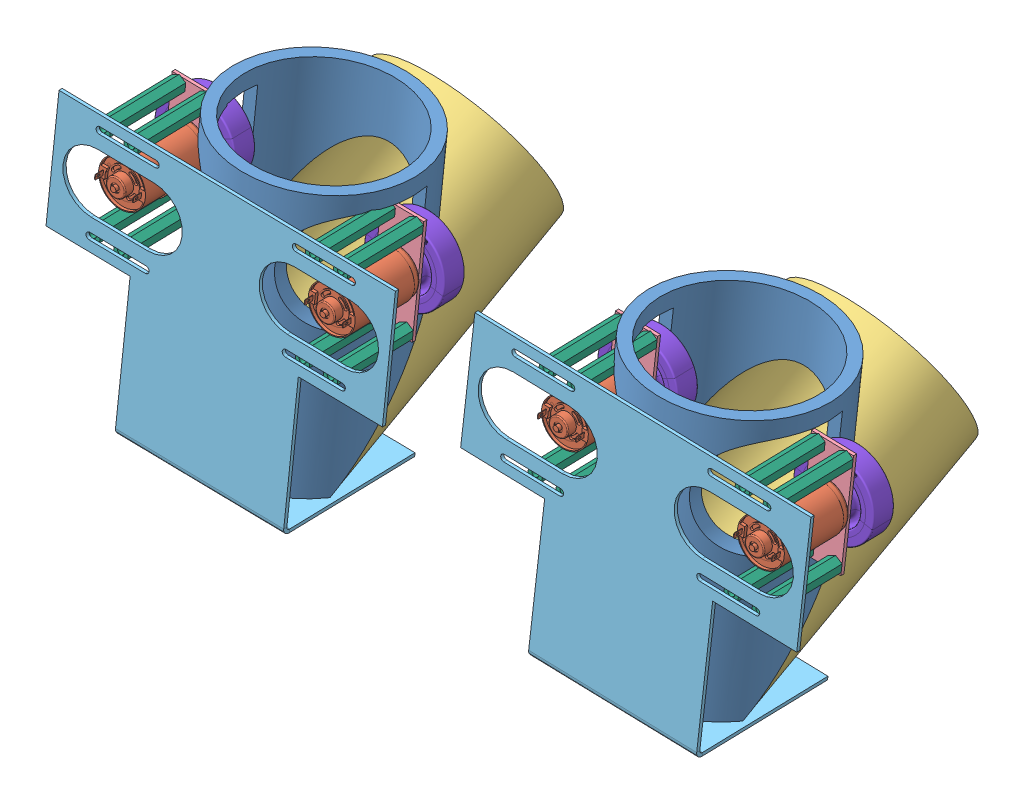
SolidWorks assembly Shooter ASM MK2, configuration Default. Lengths in mm.
Overall size (704.32 314.19 333.1).
40 component instances, 8 part files, 1 mates.
Components (placement in the parent):
- Shooter 1]2ASmMK2-1: Shooter 1]2ASmMK2 [Default] at (85.8719 -316.5617 133.3732) x (0.999973 -0.007372 0.000242) z (-0.000238 0.000428 1) size (327.38 301.67 311.41) (flexible)
  - barrellMk2-1: barrellMk2 [Default] at (-140.9196 583.647 280.9569) x (0.996255 -0.066286 -0.055525) z (-0.064337 -0.997272 0.036194) size (166.95 166.95 255.27)
  - Vex217-4347-STEP-20160210MK2-1: Vex217-4347-STEP-20160210MK2 [Default] at (-240.0878 602.0094 303.6018) x (0.057773 0.032486 0.997801) z (-0.064337 -0.997272 0.036194) size (88 44.3 44.3)
  - Vex217-4347-STEP-20160210MK2-2: Vex217-4347-STEP-20160210MK2 [Default] at (-50.8518 589.4185 293.055) x (0.057773 0.032486 0.997801) z (0.064337 0.997272 -0.036194) size (88 44.3 44.3)
  - barrellFeederMk2-1: barrellFeederMk2 [Default] at (-147.4464 482.6349 284.4398) x (-0.996255 0.066286 0.055525) z (0.017864 -0.470502 0.882218) size (166.95 166.95 254)
  - SpinMotorSideMk2-3: SpinMotorSideMk2 [Default] at (-240.0878 602.0094 303.6018) x (-0.064337 -0.997272 0.036194) z (0.996255 -0.066286 -0.055525) size (101.6 3.17 38.1)
  - SpinMotorSideMk2-5: SpinMotorSideMk2 [Default] at (-51.0352 589.3154 289.887) x (0.064337 0.997272 -0.036194) z (0.996255 -0.066286 -0.055525) size (101.6 3.17 38.1)
  - SpinMotorMk2-1: SpinMotorMk2 [Default] at (-134.6101 597.8751 377.1792) x (0.996255 -0.066286 -0.055525) z (0.064337 0.997272 -0.036194) size (304.8 133.35 248.92)
  - Mackchurro-2: Mackchurro [Default] at (-253.3988 559.7602 343.9321) x (-0.89495 -0.44123 0.066183) z (0.44241 -0.896806 0.003583) size (14.66 76.2 12.7)
  - Mackchurro-3: Mackchurro [Default] at (-222.3745 646.734 339.3041) x (0.064337 0.997272 -0.036194) z (-0.996255 0.066286 0.055525) size (14.66 76.2 12.7)
  - Mackchurro-4: Mackchurro [Default] at (-228.094 558.0766 342.5217) x (0.064337 0.997272 -0.036194) z (-0.996255 0.066286 0.055525) size (14.66 76.2 12.7)
  - Mackchurro-5: Mackchurro [Default] at (-247.6793 648.4177 340.7144) x (0.064337 0.997272 -0.036194) z (-0.996255 0.066286 0.055525) size (14.66 76.2 12.7)
  - Mackchurro-6: Mackchurro [Default] at (-33.1385 634.1431 328.7573) x (0.89495 0.44123 -0.066183) z (-0.44241 0.896806 -0.003583) size (14.66 76.2 12.7)
  - Mackchurro-7: Mackchurro [Default] at (-38.858 545.4857 331.9749) x (0.89495 0.44123 -0.066183) z (0.44241 -0.896806 0.003583) size (14.66 76.2 12.7)
  - Mackchurro-8: Mackchurro [Default] at (-64.1628 547.1693 333.3853) x (0.064337 0.997272 -0.036194) z (0.996255 -0.066286 -0.055525) size (14.66 76.2 12.7)
  - Mackchurro-9: Mackchurro [Default] at (-58.4433 635.8268 330.1676) x (0.064337 0.997272 -0.036194) z (0.996255 -0.066286 -0.055525) size (14.66 76.2 12.7)
  - Hub_T81H-RM51-1: Hub_T81H-RM51 [Default] at (-240.5234 601.7644 296.0784) x (0.896341 0.4384 -0.066171) z (-0.057773 -0.032486 -0.997801) size (20.32 20.32 20.32)
  - Wheel_T81P-29-1: Wheel_T81P-29 [Default] at (-240.5234 601.7644 296.0784) x (-0.896341 -0.4384 0.066171) z (-0.057773 -0.032486 -0.997801) size (73.03 73.03 21.34)
  - Wheel_T81P-29-2: Wheel_T81P-29 [Default] at (-51.2874 589.1736 285.5316) x (-0.966505 0.252165 0.047751) z (-0.057773 -0.032486 -0.997801) size (73.03 73.03 21.34)
  - Hub_T81H-RM51-2: Hub_T81H-RM51 [Default] at (-51.2874 589.1736 285.5316) x (0.250059 0.967139 -0.045966) z (-0.057773 -0.032486 -0.997801) size (20.32 20.32 20.32)
- Shooter 1]2ASmMK2-2: Shooter 1]2ASmMK2 [Default] at (453.9494 -326.3433 112.38) x (0.999851 -0.017239 0.00057) z (-0.000553 0.001003 0.999999) size (327.38 301.67 311.41) (flexible)
  - barrellMk2-1: barrellMk2 [Default] at (-140.9196 583.647 280.9569) x (0.996255 -0.066286 -0.055525) z (-0.064337 -0.997272 0.036194) size (166.95 166.95 255.27)
  - Vex217-4347-STEP-20160210MK2-1: Vex217-4347-STEP-20160210MK2 [Default] at (-215.1104 600.3475 302.2098) x (0.057773 0.032486 0.997801) z (-0.064337 -0.997272 0.036194) size (88 44.3 44.3)
  - Vex217-4347-STEP-20160210MK2-2: Vex217-4347-STEP-20160210MK2 [Default] at (-37.9764 588.5618 292.3374) x (0.057773 0.032486 0.997801) z (0.064337 0.997272 -0.036194) size (88 44.3 44.3)
  - barrellFeederMk2-1: barrellFeederMk2 [Default] at (-147.4464 482.6349 284.4398) x (-0.996255 0.066286 0.055525) z (0.017864 -0.470502 0.882218) size (166.95 166.95 254)
  - SpinMotorSideMk2-3: SpinMotorSideMk2 [Default] at (-215.1104 600.3475 302.2098) x (-0.064337 -0.997272 0.036194) z (0.996255 -0.066286 -0.055525) size (101.6 3.17 38.1)
  - SpinMotorSideMk2-5: SpinMotorSideMk2 [Default] at (-38.1598 588.4587 289.1694) x (0.064337 0.997272 -0.036194) z (0.996255 -0.066286 -0.055525) size (101.6 3.17 38.1)
  - SpinMotorMk2-1: SpinMotorMk2 [Default] at (-134.6101 597.8751 377.1792) x (0.996255 -0.066286 -0.055525) z (0.064337 0.997272 -0.036194) size (304.8 133.35 248.92)
  - Mackchurro-2: Mackchurro [Default] at (-228.4215 558.0983 342.54) x (-0.89495 -0.44123 0.066183) z (0.44241 -0.896806 0.003583) size (14.66 76.2 12.7)
  - Mackchurro-3: Mackchurro [Default] at (-197.3971 645.0721 337.912) x (0.064337 0.997272 -0.036194) z (-0.996255 0.066286 0.055525) size (14.66 76.2 12.7)
  - Mackchurro-4: Mackchurro [Default] at (-203.1166 556.4147 341.1297) x (0.064337 0.997272 -0.036194) z (-0.996255 0.066286 0.055525) size (14.66 76.2 12.7)
  - Mackchurro-5: Mackchurro [Default] at (-222.702 646.7558 339.3223) x (0.064337 0.997272 -0.036194) z (-0.996255 0.066286 0.055525) size (14.66 76.2 12.7)
  - Mackchurro-6: Mackchurro [Default] at (-20.263 633.2865 328.0397) x (0.89495 0.44123 -0.066183) z (-0.44241 0.896806 -0.003583) size (14.66 76.2 12.7)
  - Mackchurro-7: Mackchurro [Default] at (-25.9826 544.629 331.2573) x (0.89495 0.44123 -0.066183) z (0.44241 -0.896806 0.003583) size (14.66 76.2 12.7)
  - Mackchurro-8: Mackchurro [Default] at (-51.2874 546.3127 332.6677) x (0.064337 0.997272 -0.036194) z (0.996255 -0.066286 -0.055525) size (14.66 76.2 12.7)
  - Mackchurro-9: Mackchurro [Default] at (-45.5679 634.9701 329.45) x (0.064337 0.997272 -0.036194) z (0.996255 -0.066286 -0.055525) size (14.66 76.2 12.7)
  - Hub_T81H-RM51-1: Hub_T81H-RM51 [Default] at (-215.546 600.1026 294.6863) x (0.89195 0.447261 -0.066206) z (-0.057773 -0.032486 -0.997801) size (20.32 20.32 20.32)
  - Wheel_T81P-29-1: Wheel_T81P-29 [Default] at (-215.546 600.1026 294.6863) x (-0.89195 -0.447261 0.066206) z (-0.057773 -0.032486 -0.997801) size (73.03 73.03 21.34)
  - Wheel_T81P-29-2: Wheel_T81P-29 [Default] at (-38.412 588.3169 284.814) x (-0.968931 0.242588 0.048203) z (-0.057773 -0.032486 -0.997801) size (73.03 73.03 21.34)
  - Hub_T81H-RM51-2: Hub_T81H-RM51 [Default] at (-38.412 588.3169 284.814) x (0.240488 0.969585 -0.045492) z (-0.057773 -0.032486 -0.997801) size (20.32 20.32 20.32)
Mates (geometry in assembly coordinates):
- Coincident1: coincident aligned: plane of Shooter 1]2ASmMK2-1/SpinMotorMk2-1 through (-44.4171 282.4507 510.2652) normal (0.057773 0.032486 0.997801); plane of Shooter 1]2ASmMK2-2/SpinMotorMk2-1 through (329.4577 274.1415 488.8884) normal (0.057773 0.032486 0.997801)
